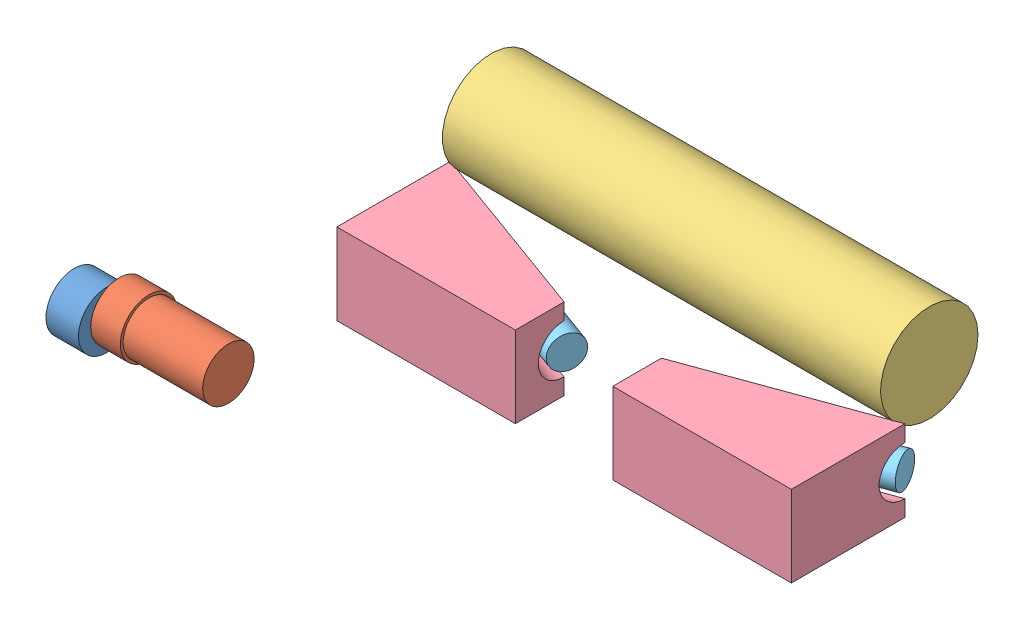
SolidWorks assembly Rough Layout Assembly, configuration Default. Lengths in mm.
Overall size (356.76 103.14 229.45).
9 component instances, 5 part files, 4 mates.
Components (placement in the parent):
- Drive Wheel Rough Assembly-1: Drive Wheel Rough Assembly [Default] at (-167.4835 0.4534 88.3585) x (0 0 -1) z (1 0 0) size (42.18 47.38 94.88)
  - Wheel - rough-1: Wheel - rough [Default] at (0 17.5 -45.8572) x (0.972576 0.232587 0) z (0 0 1) size (35 35 20)
  - Motor Barber Coleman geared-1: Motor Barber Coleman geared [Default] at (0 26.2186 0) x (0 0 1) z (-1 0 0) size (89.87 35.14 35.14)
- Collection Rough Assembly-1: Collection Rough Assembly [Default] at (-140 0 0) size (286.83 100 120)
  - Brush - rough-1: Brush - rough [Default] at (275 70 -90) x (0 0 1) z (-1 0 0) size (60 60 270)
  - Ball Guides - rough-1: Ball Guides - rough [Default] at (0 0 -30) size (110 50 70)
  - Ball Guide Roller - rough-1: Ball Guide Roller - rough [Default] at (0 25 -70) x (0.341743 0 -0.939793) z (0.939793 0 0.341743) size (20 20 120)
  - Ball Guides - rough-2: Ball Guides - rough [Default] at (280 50 -30) x (-1 0 0) z (0 0 1) size (110 50 70)
  - Ball Guide Roller - rough-2: Ball Guide Roller - rough [Default] at (280 25 -70) x (-0.341743 0 -0.939793) z (-0.939793 0 0.341743) size (20 20 120)
Mates (geometry in assembly coordinates):
- Coincident1: coincident aligned: plane of Collection Rough Assembly-1 through (-140 0 0) normal (0 0 1); plane of assembly through (0 0 0) normal (0 0 1)
- Coincident2: coincident aligned: plane of Collection Rough Assembly-1 through (-140 0 0) normal (0 1 0); plane of assembly through (0 0 0) normal (0 1 0)
- Coincident3: coincident aligned: plane of Collection Rough Assembly-1 through (0 0 0) normal (1 0 0); plane of assembly through (0 0 0) normal (1 0 0)
- Parallel1: parallel anti-aligned: plane of Drive Wheel Rough Assembly-1/Wheel - rough-1 through (-213.3407 17.9534 88.3585) normal (-1 0 0); plane of assembly through (0 0 0) normal (1 0 0)
